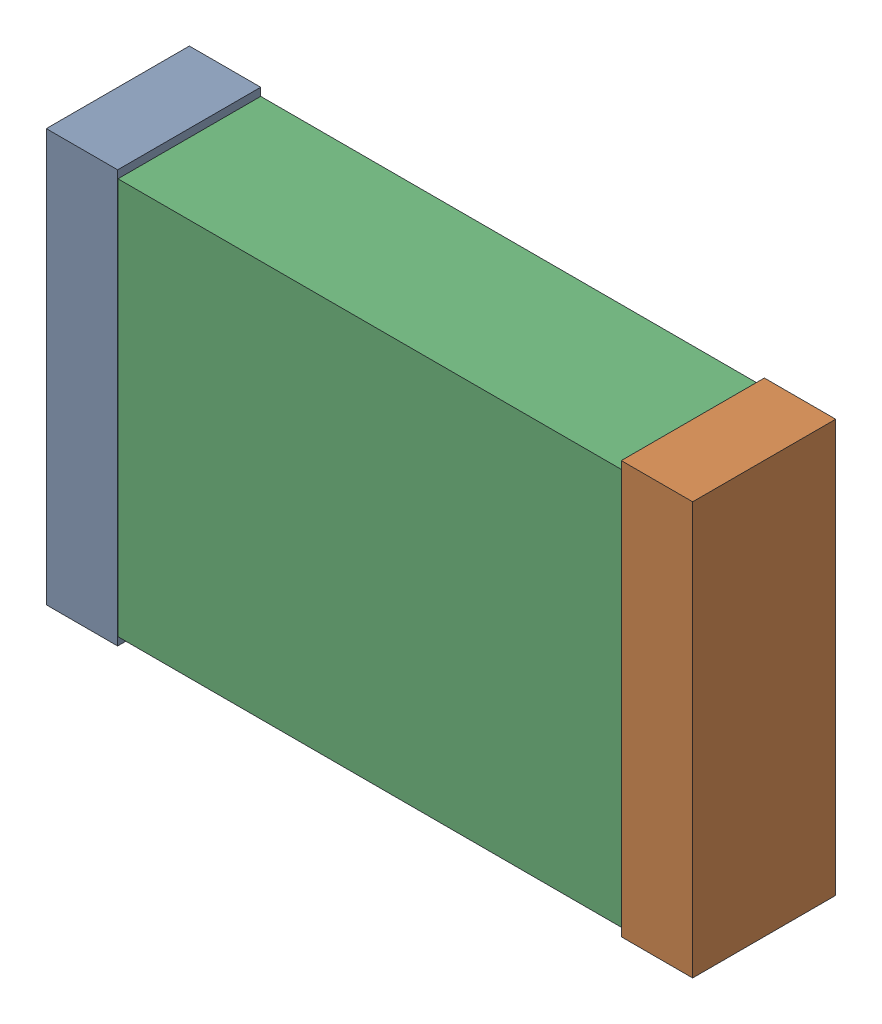
SolidWorks assembly C54, configuration Default. Lengths in mm.
Overall size (2.04 1.3 0.45).
6 component instances, 2 part files, 0 mates.
Components (placement in the parent):
- 870943360-1: 870943360 [Default] at (65.3678 22.2482 0) size (0.23 1.3 0.45)
  - Extruded_40-1: Extruded_40 [Default] at origin size (0.23 1.3 0.45)
- 870943360-2: 870943360 [Default] at (67.1803 22.2482 0) size (0.23 1.3 0.45)
  - Extruded_40-1: Extruded_40 [Default] at origin size (0.23 1.3 0.45)
- 870943200-1: 870943200 [Default] at (66.2678 22.2482 0) size (2 1.25 0.45)
  - Extruded_39-1: Extruded_39 [Default] at origin size (2 1.25 0.45)
